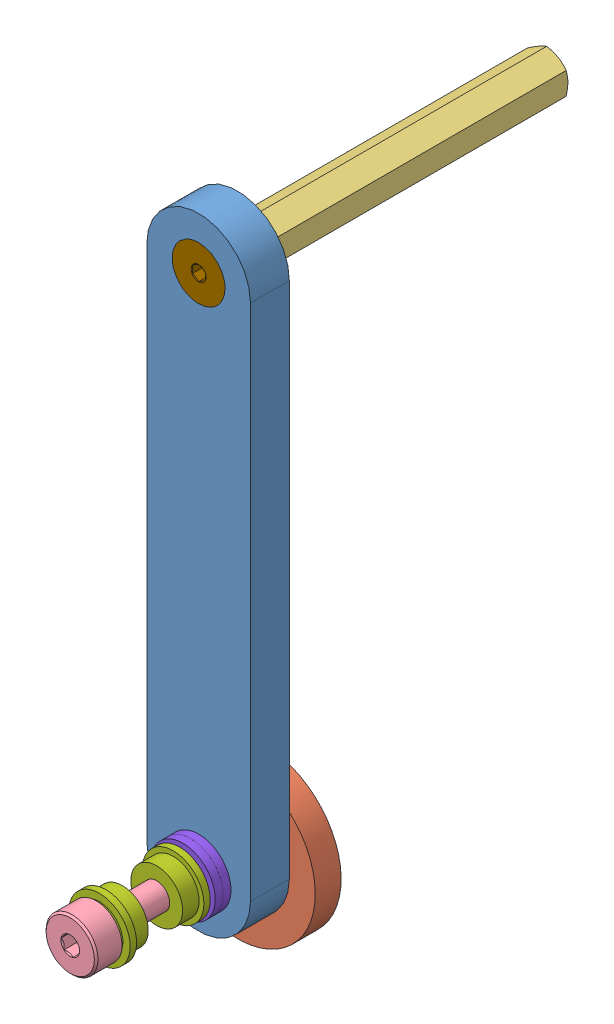
SolidWorks assembly top_link_assy, configuration Default. Lengths in mm.
Overall size (19.48 79.59 58.94).
12 component instances, 9 part files, 28 mates.
Components (placement in the parent):
- top_link-1: top_link [Default] at (0 0 4.7625) x (0 1 0) z (-1 0 0) size (76.2 4.76 12.7)
- RC22-1: RC22 [Default] at (0 -63.5 -3.175) x (0.022662 -0.999743 0) z (-0.999743 -0.022662 0) size (19.05 3.17 19.05)
- _ALUM FEM THRDED HEX STANDOFF_91780A036-1: _ALUM FEM THRDED HEX STANDOFF_91780A036 [91780A036] at (0 0 -19.05) x (0.5 0.866025 0) z (0 0 1) size (4.76 5.5 38.96)
- 4_40-5-8_5-32-94035A136-1: 4_40-5-8_5-32-94035A136 [94035A136] at (0 -63.5 20.498) x (0.736571 -0.67636 0) z (0 0 1) size (6.35 6.35 23.39)
- bearing_spacer_ 99040A316-1: bearing_spacer_ 99040A316 [Default] at (0 -63.5 7.0993) x (0.923728 0.383049 0) z (0 0 -1) size (4.76 4.76 0.41)
- bearing_spacer_ 99040A316-2: bearing_spacer_ 99040A316 [Default] at (0 -63.5 17.323) x (0.923728 0.383049 0) z (0 0 -1) size (4.76 4.76 0.41)
- 4_40_THIN_LOCKNUT_90633A005-1: 4_40_THIN_LOCKNUT_90633A005 [90633A005] at (0 -63.5 -3.175) x (0.830959 0.556334 0) z (-0.556334 0.830959 0) size (6.35 2.86 7.33)
- FR144-ZZ-1: FR144-ZZ [Default] at (0 -63.5 14.1131) x (-0.924303 -0.38166 0) z (0 0 1) size (7.52 7.52 2.8)
- 4_40-Washer_AL_93286A005-new-1: 4_40-Washer_AL_93286A005-new [93286A005] at (0 -63.5 5.7277) x (0 0 -1) z (0.99868 -0.051372 0) size (0.97 7.92 7.92)
- 4_40-Washer_AL_93286A005-new-2: 4_40-Washer_AL_93286A005-new [93286A005] at (0 -63.5 6.6929) x (0 0 -1) z (0.987351 0.158553 0) size (0.97 7.92 7.92)
- FR144-ZZ-2: FR144-ZZ [Default] at (0 -63.5 9.9028) x (-0.778572 -0.627556 0) z (0 0 -1) size (7.52 7.52 2.8)
- 4_40-625-countersunk-91253A112-1: 4_40-625-countersunk-91253A112 [91253A112] at (0 0 4.7625) size (6.48 6.48 16.21)
Mates (geometry in assembly coordinates):
- Coincident17: coincident: plane of top_link-1 through (0 0 0) normal (0 0 -1); plane of _ALUM FEM THRDED HEX STANDOFF_91780A036-1 through (35.2121 -7.2182 0) normal (0 0 1)
- Parallel1: parallel: plane of top_link-1 through (-6.35 0 0) normal (-1 0 0); plane of _ALUM FEM THRDED HEX STANDOFF_91780A036-1 through (35.2121 -7.2182 0) normal (-1 0 0)
- Coincident12: coincident anti-aligned: plane of top_link-1 through (0 0 4.7625) normal (0 0 1); plane of ? through (-0.075 -2.7041 4.7625) normal (0 0 -1)
- Concentric12: concentric anti-aligned: cylinder of top_link-1 through (0 0 0) axis (0 0 -1) radius 1.632; cylinder of ? through (0 0 6.2611) axis (0 0 1) radius 2.7051
- Concentric17: concentric aligned: cylinder of top_link-1 through (0 -63.5 0) axis (0 0 -1) radius 1.632; cylinder of RC22-1 through (0 -63.5 0) axis (0 0 -1) radius 1.5875
- Coincident22: coincident anti-aligned: plane of top_link-1 through (0 0 0) normal (0 0 -1); plane of RC22-1 through (0 -63.5 0) normal (0 0 1)
- Concentric14: concentric anti-aligned: cylinder of FR144-ZZ-2 through (0 -63.5 7.8867) axis (0 0 1) radius 1.5875; cylinder of RC22-1 through (0 -63.5 0) axis (0 0 -1) radius 1.5875
- Coincident23: coincident anti-aligned: plane of RC22-1 through (0 -63.5 -3.175) normal (0 0 -1); plane of 4_40_THIN_LOCKNUT_90633A005-1 through (0.4211 -69.836 -3.175) normal (0 0 1)
- Concentric18: concentric anti-aligned: cylinder of RC22-1 through (0 -63.5 0) axis (0 0 -1) radius 1.5875; cylinder of 4_40_THIN_LOCKNUT_90633A005-1 through (0 -63.5 -5.5663) axis (0 0 1) radius 1.1475
- Concentric13: concentric anti-aligned: circle of _ALUM FEM THRDED HEX STANDOFF_91780A036-1; circle of ?
- Concentric19: concentric aligned: cylinder of FR144-ZZ-1 through (0 -63.5 16.1292) axis (0 0 -1) radius 1.5875; cylinder of 4_40-5-8_5-32-94035A136-1 through (0 -63.5 -2.5208) axis (0 0 -1) radius 1.5875
- Concentric23: concentric anti-aligned: cylinder of 4_40-5-8_5-32-94035A136-1 through (0 -63.5 -2.5208) axis (0 0 -1) radius 1.5875; cylinder of 4_40-Washer_AL_93286A005-new-1 through (0 -63.5 4.7625) axis (0 0 1) radius 1.5875
- Concentric24: concentric anti-aligned: cylinder of 4_40-5-8_5-32-94035A136-1 through (0 -63.5 -2.5208) axis (0 0 -1) radius 1.5875; cylinder of 4_40-Washer_AL_93286A005-new-2 through (0 -63.5 5.7277) axis (0 0 1) radius 1.5875
- Concentric15: concentric aligned: cylinder of FR144-ZZ-2 through (0 -63.5 7.8867) axis (0 0 1) radius 1.5875; cylinder of bearing_spacer_ 99040A316-1 through (0 -63.5 6.6929) axis (0 0 1) radius 1.5875
- Coincident18: coincident anti-aligned: plane of FR144-ZZ-2 through (0 -63.5 7.0993) normal (0 0 -1); plane of bearing_spacer_ 99040A316-1 through (0 -63.5 7.0993) normal (0 0 1)
- Concentric16: concentric anti-aligned: cylinder of FR144-ZZ-1 through (0 -63.5 16.1292) axis (0 0 -1) radius 1.5875; cylinder of bearing_spacer_ 99040A316-2 through (0 -63.5 16.9166) axis (0 0 1) radius 1.5875
- Coincident20: coincident anti-aligned: plane of FR144-ZZ-1 through (0 -63.5 16.9166) normal (0 0 1); plane of bearing_spacer_ 99040A316-2 through (0 -63.5 16.9166) normal (0 0 -1)
- Coincident31: coincident anti-aligned: plane of 4_40-Washer_AL_93286A005-new-1 through (0 -63.5 5.7277) normal (0 0 1); plane of 4_40-Washer_AL_93286A005-new-2 through (0 -63.5 5.7277) normal (0 0 -1)
- Concentric25: concentric anti-aligned: cylinder of 4_40-5-8_5-32-94035A136-1 through (0 -63.5 -2.5208) axis (0 0 -1) radius 1.5875; cylinder of FR144-ZZ-2 through (0 -63.5 7.8867) axis (0 0 1) radius 1.5875
- Coincident33: coincident: line of top_link-1 through (-6.35 0 0) axis (0 0 1); plane of assembly
- Symmetric1: symmetric aligned: plane of top_link-1 through (-6.35 0 0) normal (-1 0 0); plane of top_link-1 through (6.35 0 0) normal (1 0 0); plane of assembly through (0 0 0) normal (1 0 0)
- Coincident34: coincident anti-aligned: plane of top_link-1 through (0 0 0) normal (0 0 -1); plane of assembly through (0 0 0) normal (0 0 1)
- Coincident35: coincident anti-aligned: plane of 4_40-5-8_5-32-94035A136-1 through (-2.1474 -65.8386 17.323) normal (0 0 -1); plane of bearing_spacer_ 99040A316-2 through (0 -63.5 17.323) normal (0 0 1)
- Coincident36: coincident anti-aligned: plane of top_link-1 through (0 0 4.7625) normal (0 0 1); plane of 4_40-Washer_AL_93286A005-new-1 through (0 -63.5 4.7625) normal (0 0 -1)
- Coincident37: coincident anti-aligned: plane of bearing_spacer_ 99040A316-1 through (0 -63.5 6.6929) normal (0 0 -1); plane of 4_40-Washer_AL_93286A005-new-2 through (0 -63.5 6.6929) normal (0 0 1)
- Concentric26: concentric: cylinder of top_link-1 through (0 0 4.7625) axis (0 0 1) radius 1.632; cylinder of 4_40-625-countersunk-91253A112-1 through (0 0 4.7625) axis (0 0 1) radius 3.2385
- Coincident38: coincident aligned: plane of top_link-1 through (0 0 4.7625) normal (0 0 1); plane of 4_40-625-countersunk-91253A112-1 through (0 -1.4224 4.7625) normal (0 0 1)
- Concentric27: concentric anti-aligned: cylinder of top_link-1 through (0 0 4.7625) axis (0 0 1) radius 1.632; circle of _ALUM FEM THRDED HEX STANDOFF_91780A036-1
